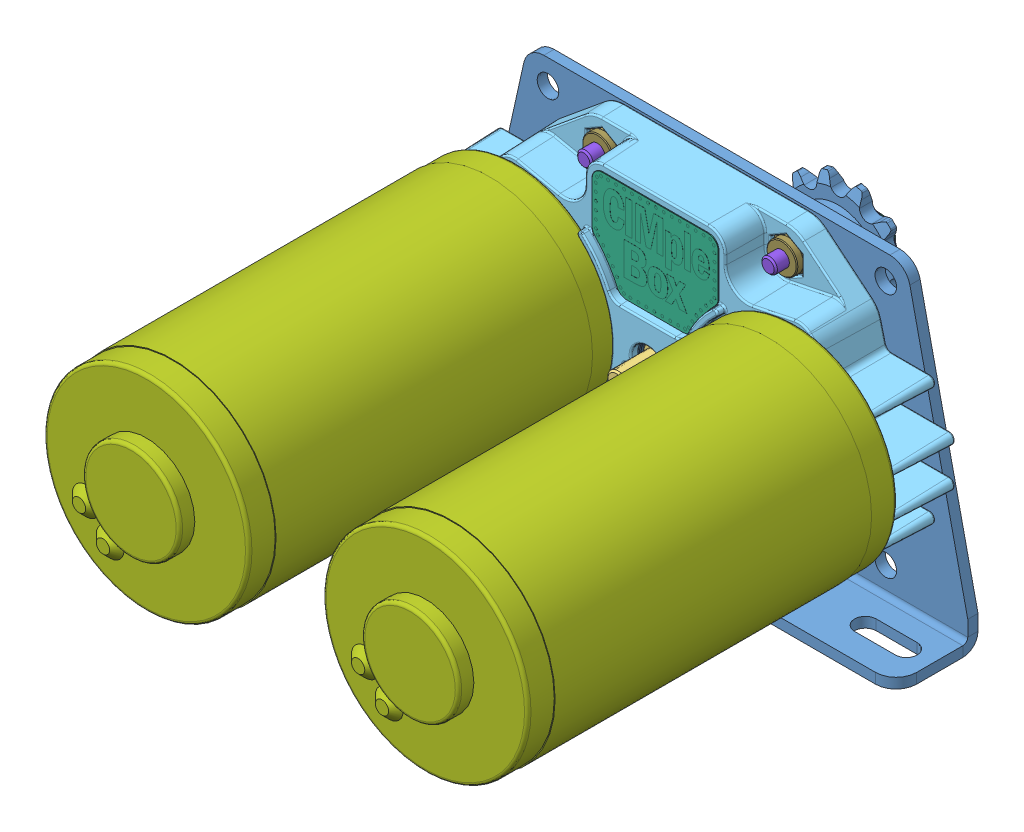
SolidWorks assembly CIMple_Box, configuration Default. Lengths in mm.
Overall size (155.57 95.25 190.12).
33 component instances, 19 part files, 71 mates.
Components (placement in the parent):
- Single_d02_-1: Single_d02_ [Default] at (0 0 -3.175) x (1 0 0) z (0 0 -1) size (155.57 95.25 25.4)
- fr-8-zz-1: fr-8-zz [Default] at (0 0 -6.3627) x (1 0 0) z (0 0 -1) size (31.74 31.74 7.94)
- Single_d03_2_-1: Single_d03_2_ [Default] at (0 0 14.7574) x (0 0 1) z (0 -1 0) size (77.22 12.7 14.66)
- 56 Tooth Output Gear-1: 56 Tooth Output Gear [Default] at (0 0 6.5151) x (0 1 0) z (0 0 1) size (71.75 71.75 9.88)
- Single d01_1-1: Single d01_1 [Default] x (-1 0 0) z (0 0 1) size (147.73 90.64 24.77)
- CIMple Box Sticker 1-1: CIMple Box Sticker 1 [Default] at (-0.0933 12.1703 19.304) size (39.12 30.48 0.53)
- CIM_motor_2-1: CIM_motor_2 [Default] at (-43.2562 0 138.4173) x (0 1 0) z (-1 0 0) size (64.01 154.93 64.01)
- 10-32x0625_shcs 1-1: 10-32x0625_shcs 1 [Default] at (-43.2499 25.39 29.2608) x (1 0 0) z (0 1 0) size (7.82 20.65 7.82)
- 10-32x0625_shcs 1-2: 10-32x0625_shcs 1 [Default] at (-43.2562 -25.4 29.2608) x (1 0 0) z (0 1 0) size (7.82 20.65 7.82)
- 2mmx2mmx10mm_key-1: 2mmx2mmx10mm_key [Default] at (-43.2562 -3.7999 3.7259) x (1 0 0) z (0 -1 0) size (2 10 2)
- r6zz 1-1: r6zz 1 [Default] at (0 0 11.8618) size (22.23 22.23 7.11)
- 10-32x0625_shcs 1-3: 10-32x0625_shcs 1 [Default] at (43.2499 25.39 29.2608) x (-1 0 0) z (0 -1 0) size (7.82 20.65 7.82)
- CIM_motor_2-2: CIM_motor_2 [Default] at (43.2682 0 138.4173) x (0 1 0) z (-1 0 0) size (64.01 154.93 64.01)
- 10-32x0625_shcs 1-4: 10-32x0625_shcs 1 [Default] at (43.2562 -25.4 29.2608) x (-1 0 0) z (0 -1 0) size (7.82 20.65 7.82)
- 2mmx2mmx10mm_key-5: 2mmx2mmx10mm_key [Default] at (43.2682 -3.7999 3.7259) x (1 0 0) z (0 -1 0) size (2 10 2)
- 12x520 CIM Gear-1: 12x520 CIM Gear [Default] at (43.2682 0 8.382) x (-0.962502 0.271274 0) z (0 0 1) size (19.3 19.3 13.21)
- 12x520 CIM Gear-2: 12x520 CIM Gear [Default] at (-43.2562 0 8.382) x (-0.96406 0.265684 0) z (0 0 1) size (19.3 19.3 13.21)
- 10-32 nylock_nut_2-1: 10-32 nylock_nut_2 [Default] at (-28.575 36.5125 4.525) x (0.5 0.866025 0) z (0.866025 -0.5 0) size (9.53 5.95 12.1)
- 10-32x0625_shcs 1-5: 10-32x0625_shcs 1 [Default] at (-28.575 36.5125 12.7) x (1 0 0) z (0 1 0) size (7.82 20.65 7.82)
- 10-32x0625_shcs 1-6: 10-32x0625_shcs 1 [Default] at (28.575 36.5125 12.7) x (1 0 0) z (0 1 0) size (7.82 20.65 7.82)
- 10-32x0625_shcs 1-7: 10-32x0625_shcs 1 [Default] at (-28.575 -36.5125 12.7) x (1 0 0) z (0 1 0) size (7.82 20.65 7.82)
- 10-32x0625_shcs 1-8: 10-32x0625_shcs 1 [Default] at (28.575 -36.5125 12.7) x (1 0 0) z (0 1 0) size (7.82 20.65 7.82)
- 10-32 nylock_nut_2-2: 10-32 nylock_nut_2 [Default] at (28.575 36.5125 4.525) x (0.5 0.866025 0) z (0.866025 -0.5 0) size (9.53 5.95 12.1)
- 10-32 nylock_nut_2-3: 10-32 nylock_nut_2 [Default] at (-28.575 -36.5125 4.525) x (0.5 0.866025 0) z (0.866025 -0.5 0) size (9.53 5.95 12.1)
- 10-32 nylock_nut_2-4: 10-32 nylock_nut_2 [Default] at (28.575 -36.5125 4.525) x (0.5 0.866025 0) z (0.866025 -0.5 0) size (9.53 5.95 12.1)
- 8mm_spring_clip-1: 8mm_spring_clip [Default] at (43.2682 0 0.8264) x (0.962502 -0.271274 0) z (-0.271274 -0.962502 0) size (14.73 1.16 14.73)
- 8mm_spring_clip-2: 8mm_spring_clip [Default] at (-43.2562 0 0.8264) x (0.96406 -0.265684 0) z (-0.265684 -0.96406 0) size (14.73 1.16 14.73)
- 125x124x700_key-1: 125x124x700_key [Default] at (-6.2992 0.0508 -21.6662) x (-1 0 0) z (0 -1 0) size (3.17 17.78 3.15)
- 14-20x0500_bhcs-1: 14-20x0500_bhcs [Default] at (0 0 -34.925) x (0 1 0) z (-1 0 0) size (11.68 16.77 11.68)
- 250_washer 1-1: 250_washer 1 [Default] at (0 0 -47.625) x (0 1 0) z (-1 0 0) size (16.26 1.57 16.26)
- 177x500_spacer_3-1: 177x500_spacer_3 [Default] at (0 0 -46.0502) x (0 1 0) z (-1 0 0) size (21.34 4.5 21.34)
- 595x500_spacer 3-1: 595x500_spacer 3 [Default] at (0 0 -21.4757) x (1 0 0) z (0 1 0) size (21.34 15.11 21.34)
- S35-12DHE Sprocket-1: S35-12DHE Sprocket [Default] at (0 0 -31.7754) size (40.24 40.24 19.56)
Mates (geometry in assembly coordinates):
- Coincident1: coincident aligned: plane of Single_d02_-1 through (-84.5463 -70.419 0) normal (0 0 1); plane of assembly through (0 0 0) normal (0 0 1)
- Coincident2: coincident anti-aligned: plane of Single_d02_-1 through (0 0 -3.175) normal (0 -1 0); plane of assembly through (0 0 0) normal (0 1 0)
- Coincident3: coincident aligned: plane of Single_d02_-1; plane of assembly through (0 0 0) normal (1 0 0)
- Concentric1: concentric anti-aligned: cylinder of Single_d02_-1 through (0 0 -3.175) axis (0 0 1) radius 14.2812; cylinder of fr-8-zz-1 through (0 0 -6.3627) axis (0 0 -1) radius 14.2875
- Coincident4: coincident anti-aligned: plane of Single_d02_-1 through (-84.5463 -70.419 0) normal (0 0 1); plane of fr-8-zz-1 through (-15.8688 0 0) normal (0 0 -1)
- Coincident5: coincident aligned: plane of fr-8-zz-1; plane of assembly through (0 0 0) normal (1 0 0)
- Concentric2: concentric aligned: cylinder of Single_d03_2_-1 through (0 0 -63.1393) axis (0 0 -1) radius 6.3373; cylinder of fr-8-zz-1 through (0 0 -6.3627) axis (0 0 -1) radius 6.35
- Coincident6: coincident anti-aligned: plane of fr-8-zz-1 through (-6.35 0 1.5748) normal (0 0 1); plane of Single_d03_2_-1 through (0 -7.3323 1.5748) normal (0 0 -1)
- Coincident7: coincident anti-aligned: plane of Single_d03_2_-1 through (0 0 14.7574) normal (0 -1 0); plane of 56 Tooth Output Gear-1
- Coincident8: coincident aligned: plane of Single_d03_2_-1; plane of 56 Tooth Output Gear-1
- Coincident9: coincident aligned: plane of Single_d03_2_-1 through (0 -7.3323 1.5748) normal (0 0 -1); plane of 56 Tooth Output Gear-1 through (0 0 1.5748) normal (0 0 -1)
- Coincident10: coincident anti-aligned: plane of Single d01_1-1 through (8.5731 15.6108 18.796) normal (0 0 1); plane of CIMple Box Sticker 1-1 through (-16.2223 26.5711 18.796) normal (0 0 -1)
- Coincident11: coincident anti-aligned: plane of Single d01_1-1 through (16.2244 42.6503 18.796) normal (0 -1 0); plane of CIMple Box Sticker 1-1 through (16.5437 42.6503 18.796) normal (0 1 0)
- Coincident12: coincident anti-aligned: plane of Single d01_1-1 through (19.7187 26.5747 18.796) normal (-1 0 0); plane of CIMple Box Sticker 1-1 through (19.7187 26.5902 18.796) normal (1 0 0)
- Concentric3: concentric aligned: cylinder of Single d01_1-1 through (-43.2562 0 -0.001) axis (0 0 1) radius 9.699; cylinder of CIM_motor_2-1 through (-43.2562 0 138.4173) axis (0 0 1) radius 4
- Coincident13: coincident anti-aligned: plane of Single d01_1-1 through (28.5753 36.5134 19.05) normal (0 0 1); plane of CIM_motor_2-1 through (-43.2562 31.75 19.05) normal (0 0 -1)
- Coincident14: coincident anti-aligned: plane of Single_d02_-1 through (-84.5463 -70.419 0) normal (0 0 1); plane of Single d01_1-1 through (28.5753 36.5134 0) normal (0 0 -1)
- Concentric5: concentric aligned: cylinder of Single d01_1-1 through (28.575 -36.5125 0) axis (0 0 1) radius 2.6245; cylinder of Single_d02_-1 through (28.575 -36.5125 -3.175) axis (0 0 1) radius 2.5527
- Concentric8: concentric aligned: cylinder of Single_d02_-1 through (-28.575 -36.5125 -3.175) axis (0 0 1) radius 2.5527; cylinder of Single d01_1-1 through (-28.575 -36.5125 0) axis (0 0 1) radius 2.6245
- Concentric9: concentric anti-aligned: cylinder of Single d01_1-1 through (-43.2562 25.4 0) axis (0 0 1) radius 2.6245; cylinder of CIM_motor_2-1 through (-43.2562 25.4 19.05) axis (0 0 -1) radius 2.0193
- Concentric11: concentric aligned: cone of Single d01_1-1 through (-43.2499 25.39 0) axis (0 0 1); cylinder of 10-32x0625_shcs 1-1 through (-43.2499 25.39 29.2608) axis (0 0 1) radius 2.3876
- Coincident16: coincident anti-aligned: plane of Single d01_1-1 through (0 0 13.3858) normal (0 0 -1); plane of 10-32x0625_shcs 1-1 through (-47.1615 25.39 13.3858) normal (0 0 1)
- Coincident17: coincident anti-aligned: plane of Single d01_1-1 through (0 0 13.3858) normal (0 0 -1); plane of 10-32x0625_shcs 1-2 through (-47.1678 -25.4 13.3858) normal (0 0 1)
- Concentric12: concentric aligned: cylinder of Single d01_1-1 through (-43.2562 -25.4 0) axis (0 0 1) radius 2.6245; cylinder of 10-32x0625_shcs 1-2 through (-43.2562 -25.4 29.2608) axis (0 0 1) radius 2.3876
- Parallel1: parallel aligned: plane of 10-32x0625_shcs 1-1 through (-43.2499 25.39 29.2608) normal (0 1 0); plane of assembly through (0 0 0) normal (0 1 0)
- Parallel2: parallel aligned: plane of 10-32x0625_shcs 1-1 through (-42.1042 23.4056 11.4046) normal (0 1 0); plane of 10-32x0625_shcs 1-2 through (-42.1105 -27.3844 11.4046) normal (0 1 0)
- Coincident20: coincident anti-aligned: plane of CIM_motor_2-1 through (-44.2562 -2.7999 13.2859) normal (0 -1 0); plane of 2mmx2mmx10mm_key-1 through (-44.2562 -2.7999 8.7259) normal (0 1 0)
- Coincident21: coincident anti-aligned: plane of CIM_motor_2-1 through (-44.2562 -4 13.2859) normal (1 0 0); plane of 2mmx2mmx10mm_key-1 through (-44.2562 -2.7999 8.7259) normal (-1 0 0)
- Concentric13: concentric aligned: cone of Single d01_1-1 through (0 0 13.3858) axis (0 0 1); cylinder of r6zz 1-1 through (0 0 11.8618) axis (0 0 1) radius 11.1125
- Coincident22: coincident anti-aligned: plane of Single d01_1-1 through (0 0 18.9738) normal (0 0 -1); plane of r6zz 1-1 through (4.7625 0 18.9738) normal (0 0 1)
- Coincident23: coincident aligned: plane of r6zz 1-1 through (0 0 11.8618) normal (1 0 0); plane of assembly through (0 0 0) normal (1 0 0)
- Coincident24: coincident anti-aligned: plane of CIM_motor_2-2 through (42.2682 -2.7999 13.2859) normal (0 -1 0); plane of 2mmx2mmx10mm_key-5 through (42.2682 -2.7999 8.7259) normal (0 1 0)
- Coincident25: coincident anti-aligned: plane of CIM_motor_2-2 through (42.2682 -4 13.2859) normal (1 0 0); plane of 2mmx2mmx10mm_key-5 through (42.2682 -2.7999 8.7259) normal (-1 0 0)
- Distance3: distance = 15.24 mm aligned: plane of CIM_motor_2-2 through (43.2682 4 -16.5141) normal (0 0 -1); plane of 2mmx2mmx10mm_key-5 through (42.2682 -4.7999 -1.2741) normal (0 0 -1)
- Concentric14: concentric anti-aligned: cylinder of CIM_motor_2-2 through (43.2682 0 138.4173) axis (0 0 1) radius 4; cylinder of 12x520 CIM Gear-1 through (43.2682 0 14.986) axis (0 0 -1) radius 4.0081
- Coincident26: coincident anti-aligned: plane of CIM_motor_2-2 through (43.2682 9.525 14.986) normal (0 0 -1); plane of 12x520 CIM Gear-1 through (43.2682 0 14.986) normal (0 0 1)
- Concentric15: concentric anti-aligned: cylinder of CIM_motor_2-1 through (-43.2562 0 138.4173) axis (0 0 1) radius 4; cylinder of 12x520 CIM Gear-2 through (-43.2562 0 14.986) axis (0 0 -1) radius 4.0081
- Coincident27: coincident anti-aligned: plane of CIM_motor_2-1 through (-43.2562 9.525 14.986) normal (0 0 -1); plane of 12x520 CIM Gear-2 through (-43.2562 0 14.986) normal (0 0 1)
- Gear1: gear = 66.04 : 19.304 mm: cylinder of 12x520 CIM Gear-1 through (43.2682 0 14.986) axis (0 0 -1) radius 9.652; cylinder of 56 Tooth Output Gear-1 through (0 0 10.9982) axis (0 0 -1) radius 33.02
- Gear2: gear = 66.04 : 19.304 mm: cylinder of 12x520 CIM Gear-2 through (-43.2562 0 14.986) axis (0 0 -1) radius 9.652; cylinder of 56 Tooth Output Gear-1 through (0 0 10.9982) axis (0 0 -1) radius 33.02
- Concentric16: concentric aligned: cylinder of Single d01_1-1 through (-28.575 36.5125 0) axis (0 0 1) radius 2.6245; cylinder of 10-32 nylock_nut_2-1 through (-28.575 36.5125 8.4944) axis (0 0 1) radius 2.0193
- Coincident29: coincident anti-aligned: plane of Single d01_1-1 through (-28.575 42.2083 2.54) normal (0 0 1); plane of 10-32 nylock_nut_2-1 through (-33.3375 39.2621 2.54) normal (0 0 -1)
- Parallel4: parallel anti-aligned: plane of 10-32 nylock_nut_2-1 through (-33.3375 39.2621 6.51) normal (-1 0 0); plane of assembly through (0 0 0) normal (1 0 0)
- Concentric17: concentric aligned: cylinder of Single_d02_-1 through (-28.575 36.5125 -3.175) axis (0 0 1) radius 2.5527; cylinder of 10-32x0625_shcs 1-5 through (-28.575 36.5125 12.7) axis (0 0 1) radius 2.3876
- Coincident31: coincident anti-aligned: plane of Single_d02_-1 through (-84.5463 -70.419 -3.175) normal (0 0 -1); plane of 10-32x0625_shcs 1-5 through (-32.4866 36.5125 -3.175) normal (0 0 1)
- Parallel5: parallel anti-aligned: plane of Single_d02_-1 through (58.7375 45.7206 0) normal (0 1 0); plane of 10-32x0625_shcs 1-5 through (-29.7207 38.4969 -5.1562) normal (0 -1 0)
- Concentric19: concentric anti-aligned: cylinder of CIM_motor_2-2 through (43.2682 0 138.4173) axis (0 0 1) radius 4; cylinder of 8mm_spring_clip-1 through (43.2682 0 0.8264) axis (0 0 -1) radius 4
- Coincident33: coincident anti-aligned: plane of 12x520 CIM Gear-1 through (43.2682 0 1.778) normal (0 0 -1); plane of 8mm_spring_clip-1 through (36.5275 1.8998 1.778) normal (0 0 1)
- Parallel6: parallel anti-aligned: plane of 8mm_spring_clip-1 through (40.7744 -5.1028 1.9147) normal (0.962502 -0.271274 0); plane of 12x520 CIM Gear-1
- Concentric20: concentric anti-aligned: cylinder of CIM_motor_2-1 through (-43.2562 0 138.4173) axis (0 0 1) radius 4; cylinder of 8mm_spring_clip-2 through (-43.2562 0 0.8264) axis (0 0 -1) radius 4
- Coincident34: coincident anti-aligned: plane of 12x520 CIM Gear-2 through (-43.2562 0 1.778) normal (0 0 -1); plane of 8mm_spring_clip-2 through (-50.0078 1.8606 1.778) normal (0 0 1)
- Parallel7: parallel aligned: plane of 8mm_spring_clip-2 through (-42.2767 -0.2699 1.9147) normal (-0.96406 0.265684 0); plane of 12x520 CIM Gear-2
- Concentric21: concentric anti-aligned: cylinder of Single_d03_2_-1 through (0 0 -63.1393) axis (0 0 -1) radius 2.4879; cylinder of 250_washer 1-1 through (0 0 -47.625) axis (0 0 1) radius 3.556
- Coincident35: coincident anti-aligned: plane of Single_d03_2_-1 through (-2.4879 0 -46.0502) normal (0 0 -1); plane of 250_washer 1-1 through (0 3.556 -46.0502) normal (0 0 1)
- Concentric22: concentric aligned: cylinder of 14-20x0500_bhcs-1 through (0 0 -34.925) axis (0 0 1) radius 3.175; cylinder of 250_washer 1-1 through (0 0 -47.625) axis (0 0 1) radius 3.556
- Coincident36: coincident anti-aligned: plane of 14-20x0500_bhcs-1 through (0 -5.842 -47.625) normal (0 0 1); plane of 250_washer 1-1 through (0 8.128 -47.625) normal (0 0 -1)
- Coincident37: coincident anti-aligned: plane of Single_d03_2_-1 through (0 0 14.7574) normal (0 -1 0); plane of 14-20x0500_bhcs-1
- Coincident38: coincident aligned: plane of 14-20x0500_bhcs-1; plane of 250_washer 1-1
- Coincident39: coincident anti-aligned: plane of Single_d03_2_-1 through (-4.7117 1.6256 -4.9276) normal (-1 0 0); plane of 125x124x700_key-1 through (-4.7117 1.6256 -39.4462) normal (1 0 0)
- Coincident40: coincident anti-aligned: plane of Single_d03_2_-1 through (-6.1253 1.6256 -4.9276) normal (0 -1 0); plane of 125x124x700_key-1 through (-4.7117 1.6256 -39.4462) normal (0 1 0)
- Distance4: distance = 6.604 mm anti-aligned: plane of 125x124x700_key-1 through (-4.7117 -1.524 -39.4462) normal (0 0 -1); plane of 250_washer 1-1 through (0 3.556 -46.0502) normal (0 0 1)
- Concentric24: concentric anti-aligned: cylinder of Single_d03_2_-1 through (0 0 -63.1393) axis (0 0 -1) radius 6.3373; cylinder of 177x500_spacer_3-1 through (0 0 -46.0502) axis (0 0 1) radius 6.6802
- Coincident41: coincident anti-aligned: plane of 250_washer 1-1 through (0 3.556 -46.0502) normal (0 0 1); plane of 177x500_spacer_3-1 through (0 10.668 -46.0502) normal (0 0 -1)
- Coincident42: coincident anti-aligned: plane of Single_d03_2_-1 through (0 0 14.7574) normal (0 -1 0); plane of 177x500_spacer_3-1
- Concentric25: concentric aligned: cylinder of Single_d03_2_-1 through (0 0 -63.1393) axis (0 0 -1) radius 6.3373; cylinder of S35-12DHE Sprocket-1 through (0 0 -21.9964) axis (0 0 -1) radius 6.4262
- Coincident43: coincident anti-aligned: plane of 177x500_spacer_3-1 through (0 6.6802 -41.5544) normal (0 0 1); plane of S35-12DHE Sprocket-1 through (0 0 -41.5544) normal (0 0 -1)
- Parallel8: parallel anti-aligned: plane of 125x124x700_key-1 through (-4.7117 -1.524 -39.4462) normal (0 -1 0); plane of S35-12DHE Sprocket-1 through (-8.0518 -1.6383 -21.9964) normal (0 1 0)
- Concentric26: concentric anti-aligned: cylinder of Single_d03_2_-1 through (0 0 -63.1393) axis (0 0 -1) radius 6.3373; cylinder of 595x500_spacer 3-1 through (0 0 -21.4757) axis (0 0 1) radius 6.6802
- Coincident45: coincident anti-aligned: plane of fr-8-zz-1 through (-14.2875 0 -6.3627) normal (0 0 -1); plane of 595x500_spacer 3-1 through (6.6802 0 -6.3627) normal (0 0 1)
- Coincident46: coincident anti-aligned: plane of Single_d03_2_-1; plane of 595x500_spacer 3-1
- Distance5: distance = 15.24 mm aligned: plane of 2mmx2mmx10mm_key-1 through (-44.2562 -4.7999 -1.2741) normal (0 0 -1); plane of CIM_motor_2-1 through (-43.2562 4 -16.5141) normal (0 0 -1)
